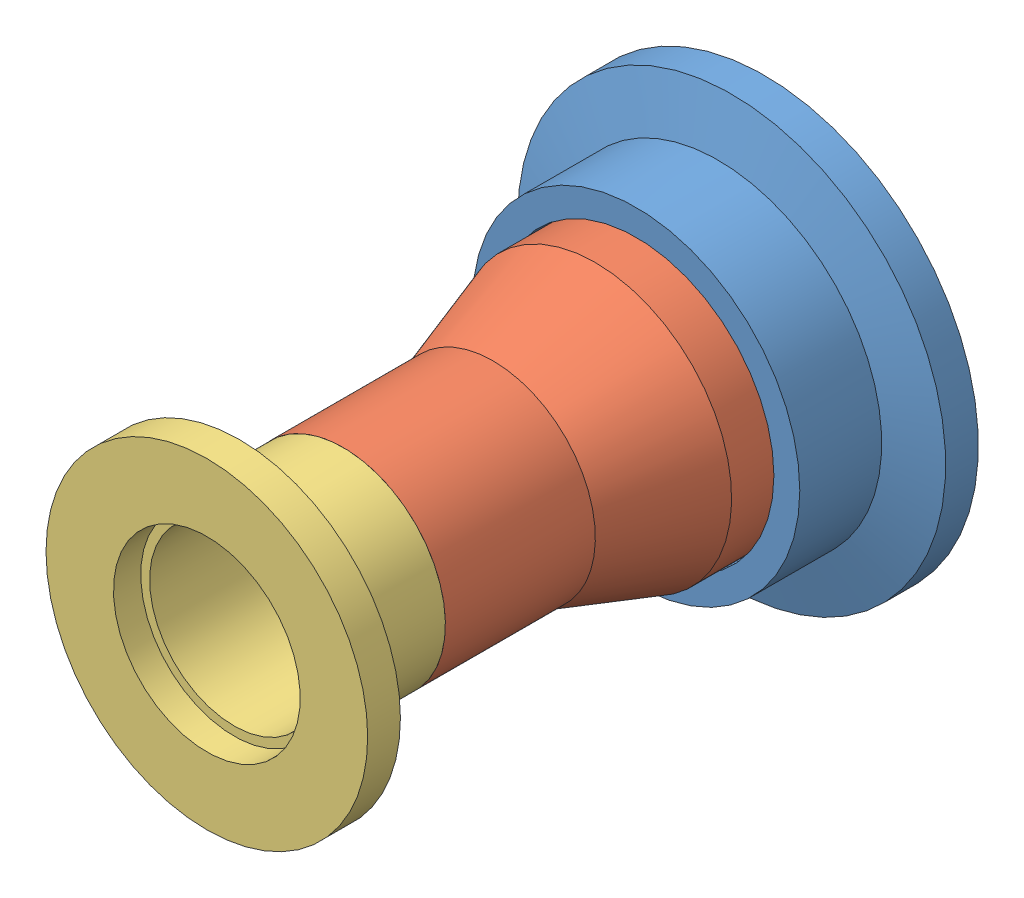
SolidWorks assembly 732006, configuration Default. Lengths in mm.
Overall size (42.3 42.3 51.94).
3 component instances, 3 part files, 4 mates.
Components (placement in the parent):
- 713002-1: 713002 [Default] at (24.3585 19.1756 19.567) size (39.88 39.88 11.94)
- 402500-1: 402500 [Default] at (24.3585 19.1756 23.885) x (-0.76579 0.64309 0) z (0 0 1) size (25.4 25.4 34.92)
- 715101-1: 715101 [Default] at (24.3585 19.1756 71.51) x (-0.749681 0.661799 0) z (0 0 -1) size (29.97 29.97 12.7)
Mates (geometry in assembly coordinates):
- Concentric1: concentric aligned: cylinder of 713002-1 through (24.3585 19.1756 19.567) axis (0 0 -1) radius 12.827; cylinder of 402500-1 through (24.3585 19.1756 23.885) axis (0 0 -1) radius 12.7
- Concentric2: concentric aligned: cylinder of 713002-1 through (24.3585 19.1756 19.567) axis (0 0 -1) radius 12.827; cylinder of 402500-1 through (24.3585 19.1756 23.885) axis (0 0 -1) radius 11.049
- Coincident2: coincident anti-aligned: plane of 713002-1 through (24.3585 19.1756 23.885) normal (0 0 1); plane of 402500-1 through (15.8973 26.2811 23.885) normal (0 0 -1)
- Coincident3: coincident anti-aligned: circle of 402500-1; circle of 715101-1
